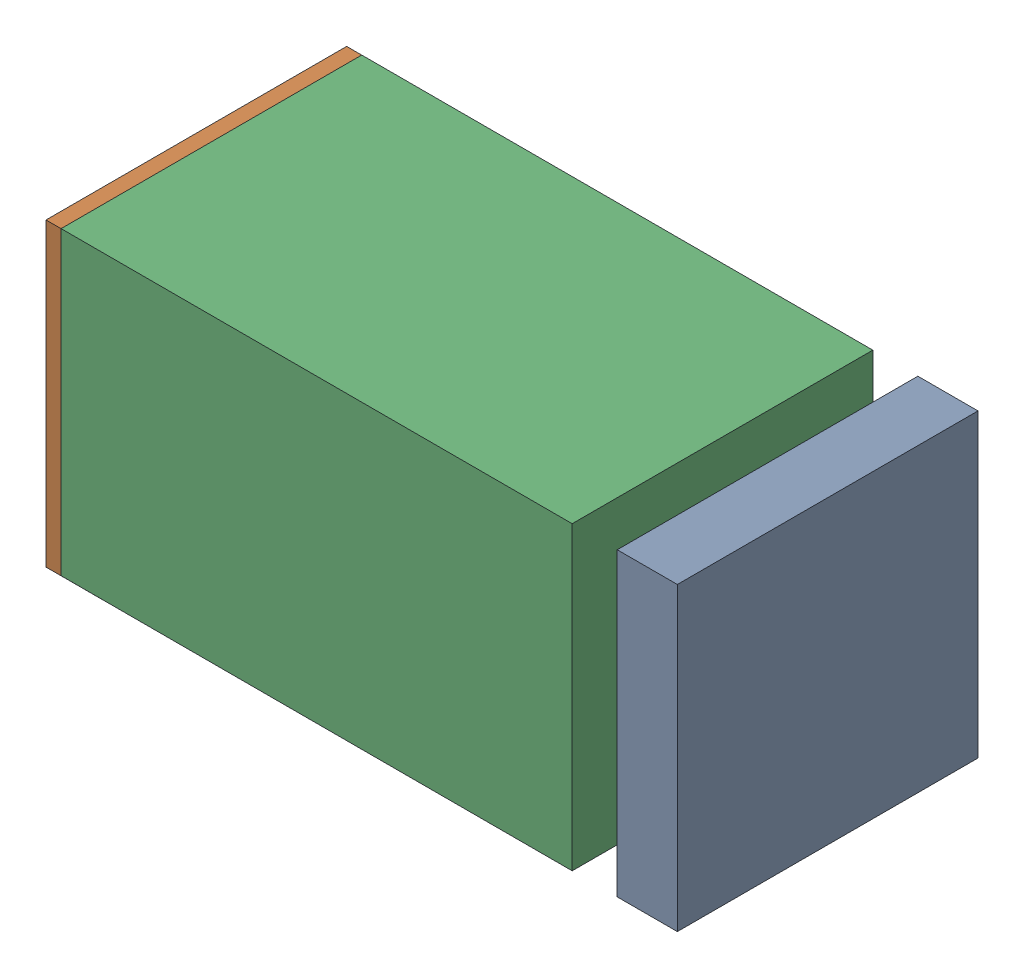
SolidWorks assembly C113, configuration Default. Lengths in mm.
Overall size (1.05 0.5 0.5).
6 component instances, 2 part files, 0 mates.
Components (placement in the parent):
- 810156080-1: 810156080 [Default] at (129 28.1 0) size (0.1 0.5 0.5)
  - Extruded_5-1: Extruded_5 [Default] at origin size (0.1 0.5 0.5)
- 810156080-2: 810156080 [Default] at (128.05 28.1 0) size (0.1 0.5 0.5)
  - Extruded_5-1: Extruded_5 [Default] at origin size (0.1 0.5 0.5)
- 810156208-1: 810156208 [Default] at (128.4501 28.1001 0) size (0.85 0.5 0.5)
  - Extruded_17-1: Extruded_17 [Default] at origin size (0.85 0.5 0.5)
